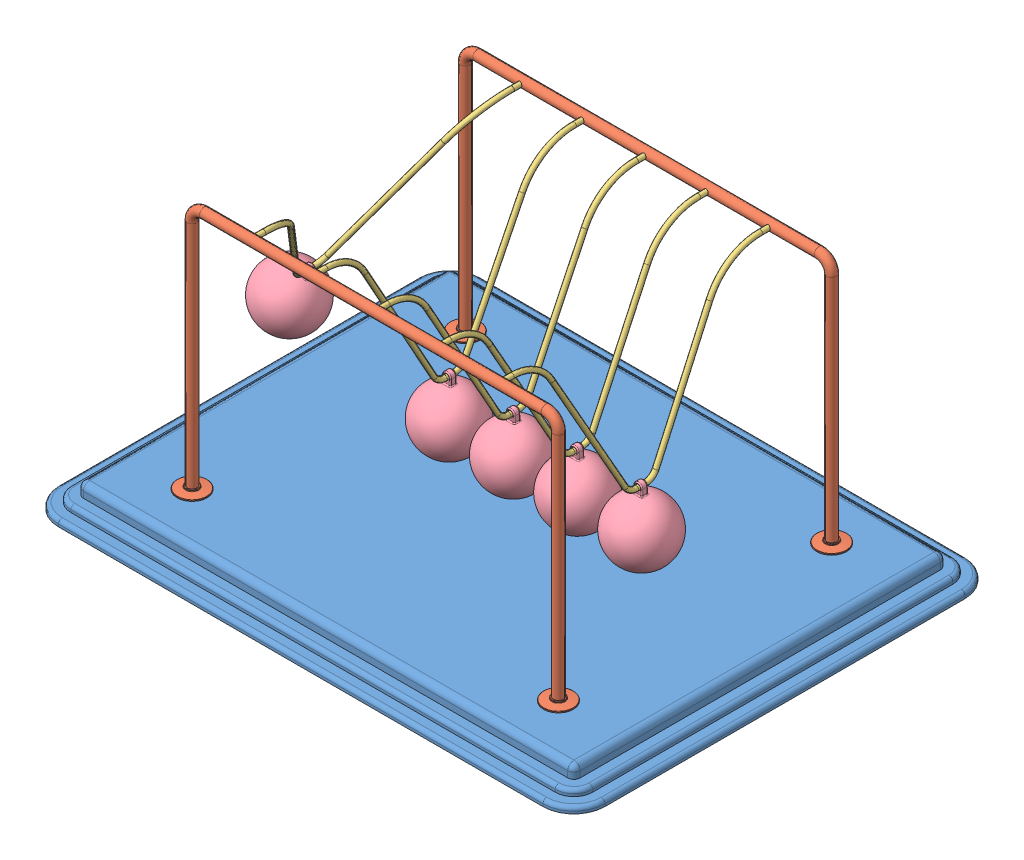
SolidWorks assembly Newtons Cradle NewtonsCradle 0233, configuration Default. Lengths in mm.
Overall size (440 222 340).
13 component instances, 4 part files, 34 mates.
Components (placement in the parent):
- Base NewtonsCradle 0233-1: Base NewtonsCradle 0233 [Default] at (-16.2968 -4.1587 11.425) size (440 20 340)
- frame NewtonsCradle 0233-1: frame NewtonsCradle 0233 [Default] at (-16.2968 144.4547 -98.575) size (319 202 24)
- frame NewtonsCradle 0233-2: frame NewtonsCradle 0233 [Default] at (-16.2968 144.4547 121.425) x (-1 0 0) z (0 0 -1) size (319 202 24)
- Hanging thing NewtonsCradle 0233-1: Hanging thing NewtonsCradle 0233 [Default] at (-157.6326 134.1825 11.425) x (0 0 1) z (-0.859985 0.510319 0) size (220 129 4)
- Hanging thing NewtonsCradle 0233-2: Hanging thing NewtonsCradle 0233 [Default] at (-66.576 122.8418 11.425) x (0 0 1) z (-0.999994 0.003446 0) size (220 129 4)
- Hanging thing NewtonsCradle 0233-3: Hanging thing NewtonsCradle 0233 [Default] at (-15.6923 122.8436 11.425) x (0 0 1) z (-0.999972 -0.007464 0) size (220 129 4)
- Hanging thing NewtonsCradle 0233-4: Hanging thing NewtonsCradle 0233 [Default] at (35.2213 122.8555 11.425) x (0 0 1) z (-0.999824 -0.018742 0) size (220 129 4)
- Hanging thing NewtonsCradle 0233-5: Hanging thing NewtonsCradle 0233 [Default] at (86.0287 122.8747 11.425) x (0 0 1) z (-0.999588 -0.028711 0) size (220 129 4)
- Sphere NewtonsCradle 0233-1: Sphere NewtonsCradle 0233 [Default] at (-195.3962 70.5436 11.425) x (0.859985 -0.510319 0) z (0 0 1) size (50 58.5 50)
- Sphere NewtonsCradle 0233-2: Sphere NewtonsCradle 0233 [Default] at (88.1533 48.9052 11.425) x (0.999588 0.028711 0) z (0 0 1) size (50 58.5 50)
- Sphere NewtonsCradle 0233-3: Sphere NewtonsCradle 0233 [Default] at (-15.14 48.8456 11.425) x (0.999972 0.007464 0) z (0 0 1) size (50 58.5 50)
- Sphere NewtonsCradle 0233-4: Sphere NewtonsCradle 0233 [Default] at (36.6081 48.8685 11.425) x (0.999824 0.018742 0) z (0 0 1) size (50 58.5 50)
- Sphere NewtonsCradle 0233-5: Sphere NewtonsCradle 0233 [Default] at (-66.831 48.8422 11.425) x (0.999994 -0.003446 0) z (0 0 1) size (50 58.5 50)
Mates (geometry in assembly coordinates):
- Coincident1: coincident anti-aligned: plane of Base-1 through (-211.2968 5.8413 156.425) normal (0 1 0); plane of frame-2 through (-175.7968 5.8413 121.425) normal (0 -1 0)
- Coincident2: coincident anti-aligned: plane of Base-1 through (-211.2968 5.8413 156.425) normal (0 1 0); plane of frame-1 through (143.2032 5.8413 -98.575) normal (0 -1 0)
- Concentric1: concentric anti-aligned: cylinder of frame-1 through (-116.2968 203.8413 -94.575) axis (0 0 -1) radius 2; cylinder of frame-2 through (-116.2968 203.8413 117.425) axis (0 0 1) radius 2
- Concentric2: concentric anti-aligned: cylinder of frame-1 through (83.7032 203.8413 -94.575) axis (0 0 -1) radius 2; cylinder of frame-2 through (83.7032 203.8413 117.425) axis (0 0 1) radius 2
- Distance1: distance = 60 mm: plane of frame-1 through (-16.2968 144.4547 -98.575) normal (0 0 1); line of Base-1 through (-211.2968 -12.1587 -158.575) axis (1 0 0)
- Distance2: distance = 60 mm: line of Base-1 through (178.7032 -12.1587 181.425) axis (-1 0 0); plane of frame-2 through (-16.2968 144.4547 121.425) normal (0 0 -1)
- Distance3: distance = 220 mm: plane of frame-2 through (-16.2968 144.4547 121.425) normal (-1 0 0); line of Base-1 through (-236.2968 -12.1587 156.425) axis (0 0 -1)
- Concentric3: concentric anti-aligned: cylinder of frame-1 through (-116.2968 203.8413 -94.575) axis (0 0 -1) radius 2; cylinder of Hanging thing-1 through (-116.2968 203.8413 111.425) axis (0 0 1) radius 2
- Concentric4: concentric anti-aligned: cylinder of frame-1 through (-116.2968 203.8413 -94.575) axis (0 0 -1) radius 2; cylinder of Hanging thing-1 through (-116.2968 203.8413 -98.575) axis (0 0 1) radius 2
- Concentric5: concentric aligned: cylinder of frame-2 through (-66.2968 203.8413 117.425) axis (0 0 1) radius 2; cylinder of Hanging thing-2 through (-66.2968 203.8413 111.425) axis (0 0 1) radius 2
- Concentric6: concentric aligned: cylinder of frame-2 through (-16.2968 203.8413 117.425) axis (0 0 1) radius 2; cylinder of Hanging thing-3 through (-16.2968 203.8413 111.425) axis (0 0 1) radius 2
- Concentric7: concentric aligned: cylinder of frame-2 through (33.7032 203.8413 117.425) axis (0 0 1) radius 2; cylinder of Hanging thing-4 through (33.7032 203.8413 111.425) axis (0 0 1) radius 2
- Concentric8: concentric aligned: cylinder of frame-2 through (83.7032 203.8413 117.425) axis (0 0 1) radius 2; cylinder of Hanging thing-5 through (83.7032 203.8413 111.425) axis (0 0 1) radius 2
- Coincident5: coincident anti-aligned: plane of frame-2 through (83.7032 203.8413 121.425) normal (0 0 -1); plane of Hanging thing-5 through (83.7032 203.8413 121.425) normal (0 0 1)
- Coincident6: coincident anti-aligned: plane of frame-2 through (33.7032 203.8413 121.425) normal (0 0 -1); plane of Hanging thing-4 through (33.7032 203.8413 121.425) normal (0 0 1)
- Coincident7: coincident anti-aligned: plane of frame-2 through (-16.2968 203.8413 121.425) normal (0 0 -1); plane of Hanging thing-3 through (-16.2968 203.8413 121.425) normal (0 0 1)
- Coincident8: coincident anti-aligned: plane of frame-2 through (-66.2968 203.8413 121.425) normal (0 0 -1); plane of Hanging thing-2 through (-66.2968 203.8413 121.425) normal (0 0 1)
- Coincident9: coincident anti-aligned: plane of frame-2 through (-116.2968 203.8413 121.425) normal (0 0 -1); plane of Hanging thing-1 through (-116.2968 203.8413 121.425) normal (0 0 1)
- Concentric9: concentric anti-aligned: cylinder of Hanging thing-1 through (-117.0163 78.8434 7.925) axis (0 0 1) radius 2; cylinder of Sphere-1 through (-117.0163 78.8434 13.925) axis (0 0 -1) radius 2
- Concentric13: concentric anti-aligned: cylinder of Hanging thing-2 through (-66.7276 78.842 7.925) axis (0 0 1) radius 2; cylinder of Sphere-5 through (-66.7276 78.842 13.925) axis (0 0 -1) radius 2
- Concentric15: concentric anti-aligned: cylinder of Hanging thing-3 through (-15.3639 78.8448 7.925) axis (0 0 1) radius 2; cylinder of Sphere-3 through (-15.3639 78.8448 13.925) axis (0 0 -1) radius 2
- Concentric16: concentric anti-aligned: cylinder of Hanging thing-5 through (87.292 78.8928 7.925) axis (0 0 1) radius 2; cylinder of Sphere-2 through (87.292 78.8928 13.925) axis (0 0 -1) radius 2
- Concentric17: concentric anti-aligned: cylinder of Hanging thing-4 through (36.0459 78.8632 7.925) axis (0 0 1) radius 2; cylinder of Sphere-4 through (36.0459 78.8632 13.925) axis (0 0 -1) radius 2
- Parallel1: parallel anti-aligned: plane of Hanging thing-1; plane of Sphere-1
- Coincident22: coincident anti-aligned: plane of Hanging thing-1; plane of Sphere-1
- Coincident12: coincident aligned: plane of Hanging thing-2 through (-66.576 122.8418 11.425) normal (0 0 1); plane of Sphere-5 through (-66.831 48.8422 11.425) normal (0 0 1)
- Coincident10: coincident aligned: plane of Hanging thing-1 through (-116.763 122.8426 11.425) normal (0 0 1); plane of Sphere-1 through (-118.5806 48.8842 11.425) normal (0 0 1)
- Coincident13: coincident anti-aligned: plane of Hanging thing-2 through (-66.576 122.8418 11.425) normal (-0.999994 0.003446 0); plane of Sphere-5 through (-66.831 48.8422 11.425) normal (0.999994 -0.003446 0)
- Coincident14: coincident anti-aligned: plane of Hanging thing-3 through (-15.6923 122.8436 11.425) normal (-0.999972 -0.007464 0); plane of Sphere-3 through (-15.14 48.8456 11.425) normal (0.999972 0.007464 0)
- Coincident15: coincident aligned: plane of Hanging thing-3 through (-15.6923 122.8436 11.425) normal (0 0 1); plane of Sphere-3 through (-15.14 48.8456 11.425) normal (0 0 1)
- Coincident18: coincident aligned: plane of Hanging thing-4 through (35.2213 122.8555 11.425) normal (0 0 1); plane of Sphere-4 through (36.6081 48.8685 11.425) normal (0 0 1)
- Coincident19: coincident anti-aligned: plane of Hanging thing-4 through (35.2213 122.8555 11.425) normal (-0.999824 -0.018742 0); plane of Sphere-4 through (36.6081 48.8685 11.425) normal (0.999824 0.018742 0)
- Coincident20: coincident anti-aligned: plane of Hanging thing-5 through (86.0287 122.8747 11.425) normal (-0.999588 -0.028711 0); plane of Sphere-2 through (88.1533 48.9052 11.425) normal (0.999588 0.028711 0)
- Coincident21: coincident aligned: plane of Hanging thing-5 through (86.0287 122.8747 11.425) normal (0 0 1); plane of Sphere-2 through (88.1533 48.9052 11.425) normal (0 0 1)
